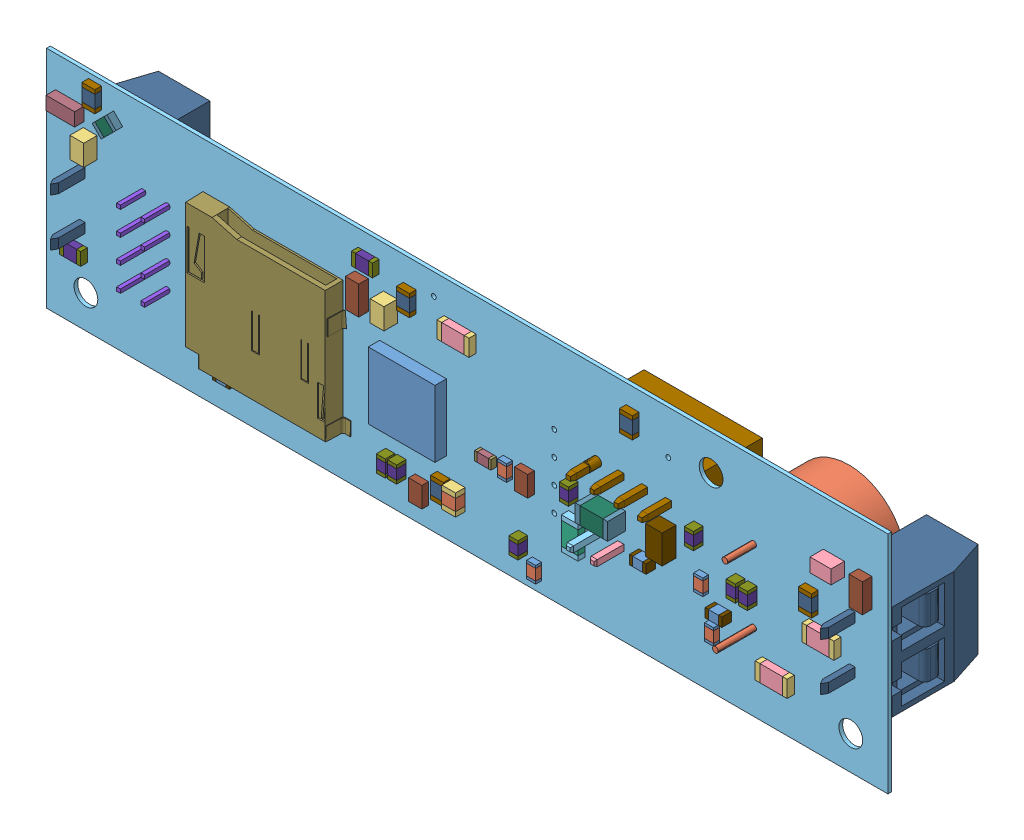
SolidWorks assembly PCB, configuration Default. Lengths in mm.
Overall size (88.26 23.62 14).
270 component instances, 41 part files, 0 mates.
Components (placement in the parent):
- R05-1: R05 [Default] at origin size (0.95 1.7 0.6)
  - 959206216-1: 959206216 [Default] at (123.9521 73.9609 0) size (0.95 0.27 0.6)
    - Extruded-1: Extruded [Default] at origin size (0.95 0.27 0.6)
  - 959206352-1: 959206352 [Default] at (123.9521 74.6759 0) size (0.95 1.16 0.6)
    - Extruded-1-1: Extruded-1 [Default] at origin size (0.95 1.16 0.6)
  - 959206216-2: 959206216 [Default] at (123.9521 75.3909 0) size (0.95 0.27 0.6)
    - Extruded-1: Extruded [Default] at origin size (0.95 0.27 0.6)
- R04-1: R04 [Default] at origin size (0.95 1.7 0.6)
  - 959206216-1: 959206216 [Default] at (141.478 81.581 0) size (0.95 0.27 0.6)
    - Extruded-1: Extruded [Default] at origin size (0.95 0.27 0.6)
  - 959206352-1: 959206352 [Default] at (141.478 82.296 0) size (0.95 1.16 0.6)
    - Extruded-1-1: Extruded-1 [Default] at origin size (0.95 1.16 0.6)
  - 959206216-2: 959206216 [Default] at (141.478 83.011 0) size (0.95 0.27 0.6)
    - Extruded-1: Extruded [Default] at origin size (0.95 0.27 0.6)
- R03-1: R03 [Default] at origin size (3.35 1.75 0.75)
  - 959206760-1: 959206760 [Default] at (147.8506 77.6516 0) size (0.49 1.75 0.75)
    - Extruded-2-1: Extruded-2 [Default] at origin size (0.49 1.75 0.75)
  - 959206896-1: 959206896 [Default] at (149.2781 77.6516 0) size (2.36 1.75 0.75)
    - Extruded-3-1: Extruded-3 [Default] at origin size (2.36 1.75 0.75)
  - 959206760-2: 959206760 [Default] at (150.7056 77.6516 0) size (0.49 1.75 0.75)
    - Extruded-2-1: Extruded-2 [Default] at origin size (0.49 1.75 0.75)
- R02-1: R02 [Default] at origin size (1.75 3.35 0.75)
  - 959207032-1: 959207032 [Default] at (128.1431 81.3844 0) size (1.75 0.49 0.75)
    - Extruded-4-1: Extruded-4 [Default] at origin size (1.75 0.49 0.75)
  - 959207168-1: 959207168 [Default] at (128.1431 79.9569 0) size (1.75 2.36 0.75)
    - Extruded-5-1: Extruded-5 [Default] at origin size (1.75 2.36 0.75)
  - 959207032-2: 959207032 [Default] at (128.1431 78.5294 0) size (1.75 0.49 0.75)
    - Extruded-4-1: Extruded-4 [Default] at origin size (1.75 0.49 0.75)
- R01-1: R01 [Default] at origin size (3.35 1.75 0.75)
  - 959206760-1: 959206760 [Default] at (117.3285 91.9479 0) size (0.49 1.75 0.75)
    - Extruded-2-1: Extruded-2 [Default] at origin size (0.49 1.75 0.75)
  - 959206896-1: 959206896 [Default] at (115.901 91.9479 0) size (2.36 1.75 0.75)
    - Extruded-3-1: Extruded-3 [Default] at origin size (2.36 1.75 0.75)
  - 959206760-2: 959206760 [Default] at (114.4735 91.9479 0) size (0.49 1.75 0.75)
    - Extruded-2-1: Extruded-2 [Default] at origin size (0.49 1.75 0.75)
- U3-1: U3 [Default] at origin size (43.25 15.95 5.5)
  - 959206080-1: 959206080 [Default] at (102.177 84.441 -2.3912) size (43.25 15.95 2)
    - Extruded-6-1: Extruded-6 [Default] at origin size (43.25 15.95 2)
  - 959205944-1: 959205944 [Default] at (85.217 88.291 -2.8912) size (0.4 0.4 5.5)
    - Extruded-7-1: Extruded-7 [Default] at origin size (0.4 0.4 5.5)
  - 959205944-2: 959205944 [Default] at (85.217 85.751 -2.8912) size (0.4 0.4 5.5)
    - Extruded-7-1: Extruded-7 [Default] at origin size (0.4 0.4 5.5)
  - 959205944-3: 959205944 [Default] at (82.677 88.291 -2.8912) size (0.4 0.4 5.5)
    - Extruded-7-1: Extruded-7 [Default] at origin size (0.4 0.4 5.5)
  - 959205944-4: 959205944 [Default] at (82.677 85.751 -2.8912) size (0.4 0.4 5.5)
    - Extruded-7-1: Extruded-7 [Default] at origin size (0.4 0.4 5.5)
  - 959205944-5: 959205944 [Default] at (85.217 83.211 -2.8912) size (0.4 0.4 5.5)
    - Extruded-7-1: Extruded-7 [Default] at origin size (0.4 0.4 5.5)
  - 959205944-6: 959205944 [Default] at (85.217 80.671 -2.8912) size (0.4 0.4 5.5)
    - Extruded-7-1: Extruded-7 [Default] at origin size (0.4 0.4 5.5)
  - 959205944-7: 959205944 [Default] at (82.677 83.211 -2.8912) size (0.4 0.4 5.5)
    - Extruded-7-1: Extruded-7 [Default] at origin size (0.4 0.4 5.5)
  - 959205944-8: 959205944 [Default] at (82.677 80.671 -2.8912) size (0.4 0.4 5.5)
    - Extruded-7-1: Extruded-7 [Default] at origin size (0.4 0.4 5.5)
- R11-1: R11 [Default] at origin size (1.35 2.2 0.7)
  - 959207304-1: 959207304 [Default] at (133.9849 94.0691 0) size (1.35 0.42 0.7)
    - Extruded-8-1: Extruded-8 [Default] at origin size (1.35 0.42 0.7)
  - 959207440-1: 959207440 [Default] at (133.9849 93.1791 0) size (1.35 1.36 0.7)
    - Extruded-9-1: Extruded-9 [Default] at origin size (1.35 1.36 0.7)
  - 959207304-2: 959207304 [Default] at (133.9849 92.2891 0) size (1.35 0.42 0.7)
    - Extruded-8-1: Extruded-8 [Default] at origin size (1.35 0.42 0.7)
- Q3-1: Q3 [Default] at origin size (1.4 3 1)
  - 959206624-1: 959206624 [Default] at (105.664 90.805 0.1) size (1.4 3 1)
    - Extruded-10-1: Extruded-10 [Default] at origin size (1.4 3 1)
- P6-1: P6 [Default] at origin size (16.31 15.21 2.47)
  - User Library-Micro SD-1: User Library-Micro SD [Default] at (103.6713 76.9862 0.04) x (-1 0 0) z (0 0 1) size (16.31 15.21 2.47)
- Q1-1: Q1 [Default] at origin size (3 1.4 1)
  - 959206488-1: 959206488 [Default] at (75.057 92.3634 0.1) size (3 1.4 1)
    - Extruded-11-1: Extruded-11 [Default] at origin size (3 1.4 1)
- C1-1: C1 [Default] at origin size (3.4 1.8 1.9)
  - 959208392-1: 959208392 [Default] at (133.022 83.687 0) size (0.5 1.8 1.9)
    - Extruded-12-1: Extruded-12 [Default] at origin size (0.5 1.8 1.9)
  - 959208392-2: 959208392 [Default] at (130.122 83.687 0) size (0.5 1.8 1.9)
    - Extruded-12-1: Extruded-12 [Default] at origin size (0.5 1.8 1.9)
  - 959208256-1: 959208256 [Default] at (131.572 83.687 0) size (2.4 1.8 1.9)
    - Extruded-13-1: Extruded-13 [Default] at origin size (2.4 1.8 1.9)
- C2-1: C2 [Default] at origin size (0.95 1.75 1)
  - 959208664-1: 959208664 [Default] at (140.8925 85.698 0) size (0.95 0.35 1)
    - Extruded-14-1: Extruded-14 [Default] at origin size (0.95 0.35 1)
  - 959208664-2: 959208664 [Default] at (140.8925 87.098 0) size (0.95 0.35 1)
    - Extruded-14-1: Extruded-14 [Default] at origin size (0.95 0.35 1)
  - 959208528-1: 959208528 [Default] at (140.8925 86.398 0) size (0.95 1.05 1)
    - Extruded-15-1: Extruded-15 [Default] at origin size (0.95 1.05 1)
- C3-1: C3 [Default] at origin size (0.95 1.75 1)
  - 959208664-1: 959208664 [Default] at (146.558 83.0961 0) size (0.95 0.35 1)
    - Extruded-14-1: Extruded-14 [Default] at origin size (0.95 0.35 1)
  - 959208664-2: 959208664 [Default] at (146.558 84.4961 0) size (0.95 0.35 1)
    - Extruded-14-1: Extruded-14 [Default] at origin size (0.95 0.35 1)
  - 959208528-1: 959208528 [Default] at (146.558 83.7961 0) size (0.95 1.05 1)
    - Extruded-15-1: Extruded-15 [Default] at origin size (0.95 1.05 1)
- C5-1: C5 [Default] at origin size (1.75 0.95 1)
  - 959208936-1: 959208936 [Default] at (142.772 80.518 0) size (0.35 0.95 1)
    - Extruded-16-1: Extruded-16 [Default] at origin size (0.35 0.95 1)
  - 959208936-2: 959208936 [Default] at (144.172 80.518 0) size (0.35 0.95 1)
    - Extruded-16-1: Extruded-16 [Default] at origin size (0.35 0.95 1)
  - 959208800-1: 959208800 [Default] at (143.472 80.518 0) size (1.05 0.95 1)
    - Extruded-17-1: Extruded-17 [Default] at origin size (1.05 0.95 1)
- C6-1: C6 [Default] at origin size (1.75 0.95 1)
  - 959208800-1: 959208800 [Default] at (135.5285 81.379 0) size (1.05 0.95 1)
    - Extruded-17-1: Extruded-17 [Default] at origin size (1.05 0.95 1)
  - 959208936-1: 959208936 [Default] at (136.2285 81.379 0) size (0.35 0.95 1)
    - Extruded-16-1: Extruded-16 [Default] at origin size (0.35 0.95 1)
  - 959208936-2: 959208936 [Default] at (134.8286 81.379 0) size (0.35 0.95 1)
    - Extruded-16-1: Extruded-16 [Default] at origin size (0.35 0.95 1)
- C7-1: C7 [Default] at origin size (0.95 1.75 1)
  - 959208528-1: 959208528 [Default] at (145.288 83.8282 0) size (0.95 1.05 1)
    - Extruded-15-1: Extruded-15 [Default] at origin size (0.95 1.05 1)
  - 959208664-1: 959208664 [Default] at (145.288 83.1282 0) size (0.95 0.35 1)
    - Extruded-14-1: Extruded-14 [Default] at origin size (0.95 0.35 1)
  - 959208664-2: 959208664 [Default] at (145.288 84.5282 0) size (0.95 0.35 1)
    - Extruded-14-1: Extruded-14 [Default] at origin size (0.95 0.35 1)
- C8-1: C8 [Default] at origin size (1.45 2.2 1)
  - 959207984-1: 959207984 [Default] at (115.697 77.2073 0) size (1.45 1.2 1)
    - Extruded-18-1: Extruded-18 [Default] at origin size (1.45 1.2 1)
  - 959207848-1: 959207848 [Default] at (115.697 78.0573 0) size (1.45 0.5 1)
    - Extruded-19-1: Extruded-19 [Default] at origin size (1.45 0.5 1)
  - 959207848-2: 959207848 [Default] at (115.697 76.3573 0) size (1.45 0.5 1)
    - Extruded-19-1: Extruded-19 [Default] at origin size (1.45 0.5 1)
- C9-1: C9 [Default] at origin size (0.95 1.75 1)
  - 959208528-1: 959208528 [Default] at (108.577 76.835 0) size (0.95 1.05 1)
    - Extruded-15-1: Extruded-15 [Default] at origin size (0.95 1.05 1)
  - 959208664-1: 959208664 [Default] at (108.577 76.135 0) size (0.95 0.35 1)
    - Extruded-14-1: Extruded-14 [Default] at origin size (0.95 0.35 1)
  - 959208664-2: 959208664 [Default] at (108.577 77.535 0) size (0.95 0.35 1)
    - Extruded-14-1: Extruded-14 [Default] at origin size (0.95 0.35 1)
- C10-1: C10 [Default] at origin size (0.95 1.75 1)
  - 959208664-1: 959208664 [Default] at (109.7632 77.5843 0) size (0.95 0.35 1)
    - Extruded-14-1: Extruded-14 [Default] at origin size (0.95 0.35 1)
  - 959208664-2: 959208664 [Default] at (109.7632 76.1843 0) size (0.95 0.35 1)
    - Extruded-14-1: Extruded-14 [Default] at origin size (0.95 0.35 1)
  - 959208528-1: 959208528 [Default] at (109.7632 76.8843 0) size (0.95 1.05 1)
    - Extruded-15-1: Extruded-15 [Default] at origin size (0.95 1.05 1)
- C11-1: C11 [Default] at origin size (0.95 1.75 1)
  - 959208664-1: 959208664 [Default] at (122.4827 75.652 0) size (0.95 0.35 1)
    - Extruded-14-1: Extruded-14 [Default] at origin size (0.95 0.35 1)
  - 959208664-2: 959208664 [Default] at (122.4827 77.052 0) size (0.95 0.35 1)
    - Extruded-14-1: Extruded-14 [Default] at origin size (0.95 0.35 1)
  - 959208528-1: 959208528 [Default] at (122.4827 76.352 0) size (0.95 1.05 1)
    - Extruded-15-1: Extruded-15 [Default] at origin size (0.95 1.05 1)
- C12-1: C12 [Default] at origin size (1.75 0.95 1)
  - 959208936-1: 959208936 [Default] at (92.521 76.327 0) size (0.35 0.95 1)
    - Extruded-16-1: Extruded-16 [Default] at origin size (0.35 0.95 1)
  - 959208936-2: 959208936 [Default] at (91.121 76.327 0) size (0.35 0.95 1)
    - Extruded-16-1: Extruded-16 [Default] at origin size (0.35 0.95 1)
  - 959208800-1: 959208800 [Default] at (91.821 76.327 0) size (1.05 0.95 1)
    - Extruded-17-1: Extruded-17 [Default] at origin size (1.05 0.95 1)
- P1-1: P1 [Default] at origin size (7.4 5.75 10.4)
  - P1-subassembly-1-1: P1-subassembly-1 [Default] at (131.5051 81.6569 -0.3912) x (-1 0 0) z (0 -1 0) size (7.4 10.4 5.75)
    - User Library-JST B2B-XH-A-1: User Library-JST B2B-XH-A [Default] at origin size (0.64 3.4 0.64)
    - User Library-JST B2B-XH-A-1-1: User Library-JST B2B-XH-A-1 [Default] at origin size (0.64 3.4 0.64)
    - User Library-JST B2B-XH-A-2-1: User Library-JST B2B-XH-A-2 [Default] at origin size (0.64 4.5 0.64)
    - User Library-JST B2B-XH-A-3-1: User Library-JST B2B-XH-A-3 [Default] at origin size (0.64 4.5 0.64)
    - User Library-JST B2B-XH-A-4-1: User Library-JST B2B-XH-A-4 [Default] at origin size (7.4 7 5.75)
- P3-1: P3 [Default] at origin size (12.4 5.75 10.4)
  - SW3dPS-jst-b4b-xh-a-1-1: SW3dPS-jst-b4b-xh-a-1 [Default] at (134.0049 88.1301 -0.3912) x (-1 0 0) z (0 -1 0) size (12.4 10.4 5.75)
- P4-1: P4 [Default] at origin
  - connector-1: connector [Default] at (76.2639 56.9549 -0.3912) x (0 1 0) z (0 0 -1)
- P5-1: P5 [Default] at origin
  - connector-1: connector [Default] at (157.0351 111.9551 -0.3912) x (0 -1 0) z (0 0 -1)
- Q2-1: Q2 [Default] at origin size (1.4 3 1)
  - 959206624-1: 959206624 [Default] at (158.496 90.17 0.1) size (1.4 3 1)
    - Extruded-10-1: Extruded-10 [Default] at origin size (1.4 3 1)
- R1-1: R1 [Default] at origin size (0.95 1.7 0.6)
  - 959206216-1: 959206216 [Default] at (142.6211 77.6287 0) size (0.95 0.27 0.6)
    - Extruded-1: Extruded [Default] at origin size (0.95 0.27 0.6)
  - 959206352-1: 959206352 [Default] at (142.6211 78.3437 0) size (0.95 1.16 0.6)
    - Extruded-1-1: Extruded-1 [Default] at origin size (0.95 1.16 0.6)
  - 959206216-2: 959206216 [Default] at (142.6211 79.0587 0) size (0.95 0.27 0.6)
    - Extruded-1: Extruded [Default] at origin size (0.95 0.27 0.6)
- R2-1: R2 [Default] at origin size (1.4 2.15 0.7)
  - 959208120-1: 959208120 [Default] at (111.8912 75.852 0) size (1.4 2.15 0.7)
    - Extruded-20-1: Extruded-20 [Default] at origin size (1.4 2.15 0.7)
- R3-1: R3 [Default] at origin size (1.35 2.2 0.7)
  - 959207304-1: 959207304 [Default] at (114.1729 78.1061 0) size (1.35 0.42 0.7)
    - Extruded-8-1: Extruded-8 [Default] at origin size (1.35 0.42 0.7)
  - 959207440-1: 959207440 [Default] at (114.1729 77.2161 0) size (1.35 1.36 0.7)
    - Extruded-9-1: Extruded-9 [Default] at origin size (1.35 1.36 0.7)
  - 959207304-2: 959207304 [Default] at (114.1729 76.3261 0) size (1.35 0.42 0.7)
    - Extruded-8-1: Extruded-8 [Default] at origin size (1.35 0.42 0.7)
- R4-1: R4 [Default] at origin size (1.7 0.95 0.6)
  - 959209072-1: 959209072 [Default] at (119.5871 82.2961 0) size (0.27 0.95 0.6)
    - Extruded-21-1: Extruded-21 [Default] at origin size (0.27 0.95 0.6)
  - 959209208-1: 959209208 [Default] at (118.8721 82.2961 0) size (1.16 0.95 0.6)
    - Extruded-22-1: Extruded-22 [Default] at origin size (1.16 0.95 0.6)
  - 959209072-2: 959209072 [Default] at (118.1571 82.2961 0) size (0.27 0.95 0.6)
    - Extruded-21-1: Extruded-21 [Default] at origin size (0.27 0.95 0.6)
- R5-1: R5 [Default] at origin size (0.95 1.7 0.6)
  - 959206216-1: 959206216 [Default] at (120.9041 81.6699 0) size (0.95 0.27 0.6)
    - Extruded-1: Extruded [Default] at origin size (0.95 0.27 0.6)
  - 959206352-1: 959206352 [Default] at (120.9041 82.3849 0) size (0.95 1.16 0.6)
    - Extruded-1-1: Extruded-1 [Default] at origin size (0.95 1.16 0.6)
  - 959206216-2: 959206216 [Default] at (120.9041 83.0999 0) size (0.95 0.27 0.6)
    - Extruded-1: Extruded [Default] at origin size (0.95 0.27 0.6)
- R6-1: R6 [Default] at origin size (1.4 2.15 0.7)
  - 959208120-1: 959208120 [Default] at (122.9827 82.385 0) size (1.4 2.15 0.7)
    - Extruded-20-1: Extruded-20 [Default] at origin size (1.4 2.15 0.7)
- R8-1: R8 [Default] at origin size (2.51 2.51 0.7)
  - 959207576-1: 959207576 [Default] at (78.6187 92.1936 0) size (1.25 1.25 0.7)
    - Extruded-23-1: Extruded-23 [Default] at origin size (1.25 1.25 0.7)
  - 959207712-1: 959207712 [Default] at (79.248 92.8229 0) size (1.92 1.92 0.7)
    - Extruded-24-1: Extruded-24 [Default] at origin size (1.92 1.92 0.7)
  - 959207576-2: 959207576 [Default] at (79.8773 93.4522 0) size (1.25 1.25 0.7)
    - Extruded-23-1: Extruded-23 [Default] at origin size (1.25 1.25 0.7)
- R13-1: R13 [Default] at origin size (2.2 1.35 0.7)
  - 959209344-1: 959209344 [Default] at (105.4089 93.8529 0) size (0.42 1.35 0.7)
    - Extruded-25-1: Extruded-25 [Default] at origin size (0.42 1.35 0.7)
  - 959209480-1: 959209480 [Default] at (106.2989 93.8529 0) size (1.36 1.35 0.7)
    - Extruded-26-1: Extruded-26 [Default] at origin size (1.36 1.35 0.7)
  - 959209344-2: 959209344 [Default] at (107.1889 93.8529 0) size (0.42 1.35 0.7)
    - Extruded-25-1: Extruded-25 [Default] at origin size (0.42 1.35 0.7)
- R7-1: R7 [Default] at origin size (2.2 1.35 0.7)
  - 959209344-1: 959209344 [Default] at (76.5821 79.5961 0) size (0.42 1.35 0.7)
    - Extruded-25-1: Extruded-25 [Default] at origin size (0.42 1.35 0.7)
  - 959209480-1: 959209480 [Default] at (75.6921 79.5961 0) size (1.36 1.35 0.7)
    - Extruded-26-1: Extruded-26 [Default] at origin size (1.36 1.35 0.7)
  - 959209344-2: 959209344 [Default] at (74.8021 79.5961 0) size (0.42 1.35 0.7)
    - Extruded-25-1: Extruded-25 [Default] at origin size (0.42 1.35 0.7)
- R9-1: R9 [Default] at origin size (1.35 2.2 0.7)
  - 959207304-1: 959207304 [Default] at (77.5971 95.5049 0) size (1.35 0.42 0.7)
    - Extruded-8-1: Extruded-8 [Default] at origin size (1.35 0.42 0.7)
  - 959207440-1: 959207440 [Default] at (77.5971 94.6149 0) size (1.35 1.36 0.7)
    - Extruded-9-1: Extruded-9 [Default] at origin size (1.35 1.36 0.7)
  - 959207304-2: 959207304 [Default] at (77.5971 93.7249 0) size (1.35 0.42 0.7)
    - Extruded-8-1: Extruded-8 [Default] at origin size (1.35 0.42 0.7)
- R14-1: R14 [Default] at origin size (1.35 2.2 0.7)
  - 959207304-1: 959207304 [Default] at (110.6132 93.495 0) size (1.35 0.42 0.7)
    - Extruded-8-1: Extruded-8 [Default] at origin size (1.35 0.42 0.7)
  - 959207440-1: 959207440 [Default] at (110.6132 92.605 0) size (1.35 1.36 0.7)
    - Extruded-9-1: Extruded-9 [Default] at origin size (1.35 1.36 0.7)
  - 959207304-2: 959207304 [Default] at (110.6132 91.715 0) size (1.35 0.42 0.7)
    - Extruded-8-1: Extruded-8 [Default] at origin size (1.35 0.42 0.7)
- R10-1: R10 [Default] at origin size (3.35 1.75 0.75)
  - 959206760-1: 959206760 [Default] at (152.7506 83.5661 0) size (0.49 1.75 0.75)
    - Extruded-2-1: Extruded-2 [Default] at origin size (0.49 1.75 0.75)
  - 959206896-1: 959206896 [Default] at (154.1781 83.5661 0) size (2.36 1.75 0.75)
    - Extruded-3-1: Extruded-3 [Default] at origin size (2.36 1.75 0.75)
  - 959206760-2: 959206760 [Default] at (155.6056 83.5661 0) size (0.49 1.75 0.75)
    - Extruded-2-1: Extruded-2 [Default] at origin size (0.49 1.75 0.75)
- R12-1: R12 [Default] at origin size (1.35 2.2 0.7)
  - 959207304-1: 959207304 [Default] at (152.7811 87.2879 0) size (1.35 0.42 0.7)
    - Extruded-8-1: Extruded-8 [Default] at origin size (1.35 0.42 0.7)
  - 959207440-1: 959207440 [Default] at (152.7811 86.3979 0) size (1.35 1.36 0.7)
    - Extruded-9-1: Extruded-9 [Default] at origin size (1.35 1.36 0.7)
  - 959207304-2: 959207304 [Default] at (152.7811 85.5079 0) size (1.35 0.42 0.7)
    - Extruded-8-1: Extruded-8 [Default] at origin size (1.35 0.42 0.7)
- U1-1: U1 [Default] at origin size (1.75 3 1.45)
  - 959209616-1: 959209616 [Default] at (137.668 84.449 0) size (1.75 3 1.45)
    - Extruded-27-1: Extruded-27 [Default] at origin size (1.75 3 1.45)
- U4-1: U4 [Default] at origin size (7 7 1.2)
  - 959209752-1: 959209752 [Default] at (110.9632 83.702 0) size (7 7 1.2)
    - Extruded-28-1: Extruded-28 [Default] at origin size (7 7 1.2)
- BUZ1-1: BUZ1 [Default] at origin size (12 12 14)
  - SW3dPS-WST-1203UX-1: SW3dPS-WST-1203UX [Default] at (146.685 84.5049 -0.4912) x (0 -1 0) z (1 0 0) size (12 14 12)
- C4-1: C4 [Default] at origin size (0.95 1.75 1)
  - 959208528-1: 959208528 [Default] at (127.791 83.885 0) size (0.95 1.05 1)
    - Extruded-15-1: Extruded-15 [Default] at origin size (0.95 1.05 1)
  - 959208664-1: 959208664 [Default] at (127.791 83.185 0) size (0.95 0.35 1)
    - Extruded-14-1: Extruded-14 [Default] at origin size (0.95 0.35 1)
  - 959208664-2: 959208664 [Default] at (127.791 84.585 0) size (0.95 0.35 1)
    - Extruded-14-1: Extruded-14 [Default] at origin size (0.95 0.35 1)
- D1-1: D1 [Default] at origin size (1.45 2.2 1.4)
  - 959209888-1: 959209888 [Default] at (77.089 89.876 0) size (1.45 2.2 1.4)
    - Extruded-29-1: Extruded-29 [Default] at origin size (1.45 2.2 1.4)
- D2-1: D2 [Default] at origin size (2.2 1.45 1.4)
  - 959210024-1: 959210024 [Default] at (155.107 90.769 0) size (2.2 1.45 1.4)
    - Extruded-30-1: Extruded-30 [Default] at origin size (2.2 1.45 1.4)
- D3-1: D3 [Default] at origin size (1.45 2.2 1.4)
  - 959209888-1: 959209888 [Default] at (108.585 90.769 0) size (1.45 2.2 1.4)
    - Extruded-29-1: Extruded-29 [Default] at origin size (1.45 2.2 1.4)
- Board-1: Board [Default] at origin size (88.26 23.62 0.39)
